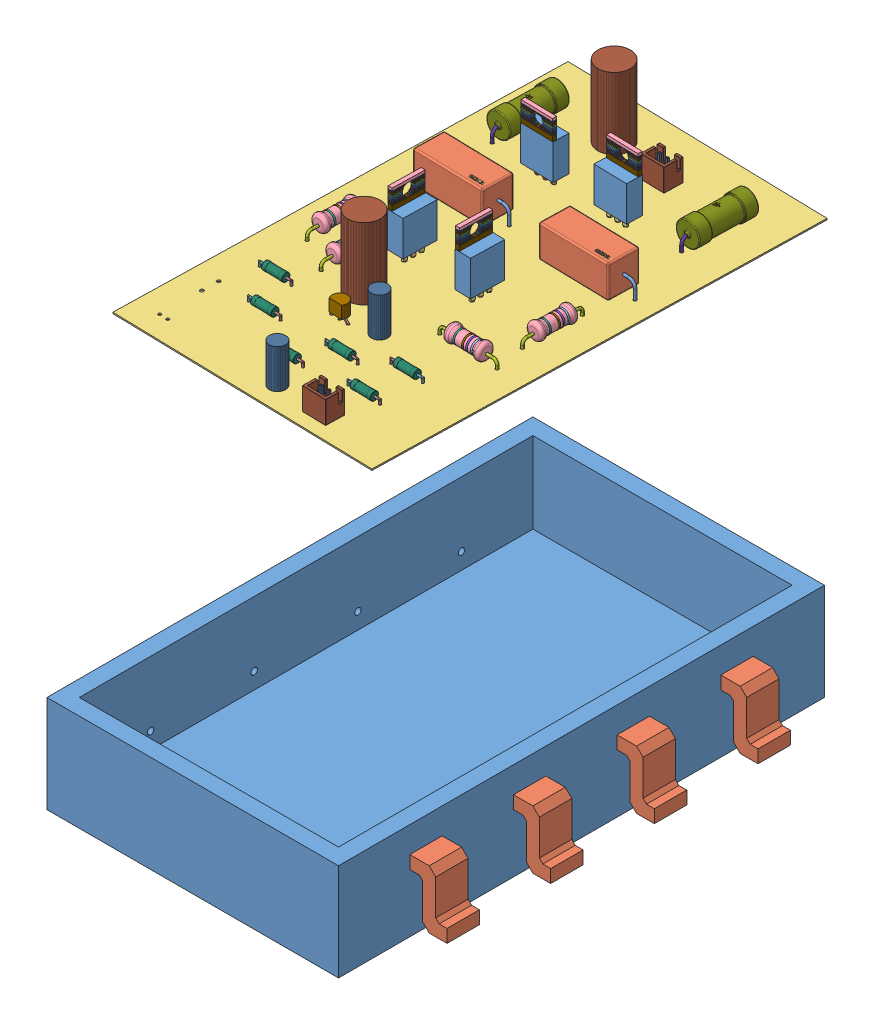
SolidWorks assembly opamp, configuration Default. Lengths in mm.
Overall size (208.13 39 264.23).
474 component instances, 67 part files, 9 mates.
Components (placement in the parent):
- OPAMP_Shyamal-1: OPAMP_Shyamal [Default] at (4.6207 72.5871 193.2104) size (90 30 150)
- OPAMP_PIN-3: OPAMP_PIN [Default] at (6.6207 90.5871 65.2104) x (-1 0 0) z (0 0 -1) size (13.5 18 10)
- OPAMP_PIN-5: OPAMP_PIN [Default] at (6.6207 90.5871 97.2104) x (-1 0 0) z (0 0 -1) size (13.5 18 10)
- OPAMP_PIN-8: OPAMP_PIN [Default] at (6.6207 90.5871 129.2104) x (-1 0 0) z (0 0 -1) size (13.5 18 10)
- OPAMP_PIN-10: OPAMP_PIN [Default] at (6.6207 90.5871 161.2104) x (-1 0 0) z (0 0 -1) size (13.5 18 10)
- OPAMP_PIN-12: OPAMP_PIN [Default] at (92.6207 90.5871 171.2104) size (13.5 18 10)
- OPAMP_PIN-14: OPAMP_PIN [Default] at (92.6207 90.5871 139.2104) size (13.5 18 10)
- OPAMP_PIN-16: OPAMP_PIN [Default] at (92.6207 90.5871 107.2104) size (13.5 18 10)
- OPAMP_PIN-18: OPAMP_PIN [Default] at (92.6207 90.5871 75.2104) size (13.5 18 10)
- PCB1-1: PCB1 [Default] at (-20.1126 88.7696 68.1609) x (0.023644 0 -0.99972) z (0 1 0) size (137.29 81.92 39)
  - PCB1.step-1: PCB1.step [Default] at origin size (137.29 81.92 39)
    - Board.step-1: Board.step [Default] at origin size (137.29 81.92 0.41)
      - Open CASCADE STEP translator 6.8 1.1.1.step-1: Open CASCADE STEP translator 6.8 1.1.1.step [Default] at (0 0 -0.4115) size (137.29 81.92 0.41)
    - R61.step-1: R61.step [Default] at origin size (18.91 5.72 7.96)
      - Res_Yageo_KNP100JR-73-22R_eec.step-1: Res_Yageo_KNP100JR-73-22R_eec.step [Default] at (64.389 10.414 0) x (-1 0 0) z (0 0 1) size (18.91 5.72 7.96)
        - 1.step-1: 1.step [Default] at (0 0 2.55) size (11.5 5.1 5.1)
        - 2.step-1: 2.step [Default] at (-3.2931 0 2.55) x (0 0 -1) z (1 0 0) size (4.2 4.2 0.5)
        - 3.step-1: 3.step [Default] at (2.7931 0 2.55) x (0 -0.492137 0.870518) z (-1 0 0) size (4.2 4.2 0.5)
        - 4.step-1: 4.step [Default] at (0 0 -2.55) size (18.91 0.8 5.21)
        - 5.step-1: 5.step [Default] at (-1.7931 0 2.55) x (0 0 -1) z (1 0 0) size (4.2 4.2 0.5)
        - 6.step-1: 6.step [Default] at (0.0069 0 2.55) x (0 -0.017206 0.999852) z (-1 0 0) size (4.2 4.2 0.5)
    - R51.step-1: R51.step [Default] at origin size (18.91 5.72 7.96)
      - Res_Yageo_KNP100JR-73-22R_eec.step-1: Res_Yageo_KNP100JR-73-22R_eec.step [Default] at (52.832 61.976 0) x (1 0 0) z (0 0 1) size (18.91 5.72 7.96)
        - 1.step-1: 1.step [Default] at (0 0 2.55) size (11.5 5.1 5.1)
        - 2.step-1: 2.step [Default] at (-3.2931 0 2.55) x (0 0 -1) z (1 0 0) size (4.2 4.2 0.5)
        - 3.step-1: 3.step [Default] at (2.7931 0 2.55) x (0 -0.492137 0.870518) z (-1 0 0) size (4.2 4.2 0.5)
        - 4.step-1: 4.step [Default] at (0 0 -2.55) size (18.91 0.8 5.21)
        - 5.step-1: 5.step [Default] at (-1.7931 0 2.55) x (0 0 -1) z (1 0 0) size (4.2 4.2 0.5)
        - 6.step-1: 6.step [Default] at (0.0069 0 2.55) x (0 -0.017206 0.999852) z (-1 0 0) size (4.2 4.2 0.5)
    - output.step-1: output.step [Default] at origin size (5.75 7.4 10.4)
      - Conn_JST_B2B-XH-A_LF_SN_eec.step-1: Conn_JST_B2B-XH-A_LF_SN_eec.step [Default] at (120.887 35.072 0) x (0 -1 0) z (0 0 1) size (7.4 5.75 10.4)
        - 1-0.step-1: 1-0.step [Default] at (0 0.025 0) x (-1 0 0) z (0 1 0) size (7.4 10.4 5.75)
          - 1-1.step-1: 1-1.step [Default] at origin size (3.14 10.2 0.64)
          - B2B-XH-A.step-1: B2B-XH-A.step [Default] at origin size (7.4 7 5.75)
          - JST_Logo_adjustable.step-1: JST_Logo_adjustable.step [Default] at (-1.7267 5.5034 2.841) size (0.85 2.3 0.01)
    - input.step-1: input.step [Default] at origin size (5.75 7.4 10.4)
      - Conn_JST_B2B-XH-A_LF_SN_eec.step-1: Conn_JST_B2B-XH-A_LF_SN_eec.step [Default] at (6.841 22.499 0) x (0 -1 0) z (0 0 1) size (7.4 5.75 10.4)
        - 1-0.step-1: 1-0.step [Default] at (0 0.025 0) x (-1 0 0) z (0 1 0) size (7.4 10.4 5.75)
          - 1-1.step-1: 1-1.step [Default] at origin size (3.14 10.2 0.64)
          - B2B-XH-A.step-1: B2B-XH-A.step [Default] at origin size (7.4 7 5.75)
          - JST_Logo_adjustable.step-1: JST_Logo_adjustable.step [Default] at (-1.7267 5.5034 2.841) size (0.85 2.3 0.01)
    - RE.step-1: RE.step [Default] at origin size (2.5 10.6 6.5)
      - Res_Vishay_BC_Components_MRS25000C1101FCT00_eec.step-1: Res_Vishay_BC_Components_MRS25000C1101FCT00_eec.step [Default] at (30.607 20.955 0) x (0 -1 0) z (0 0 1) size (2.05 0.6 5.55)
      - Res_Vishay_BC_Components_MRS25000C1101FCT00_eec-2.step-1: Res_Vishay_BC_Components_MRS25000C1101FCT00_eec-2.step [Default] at (30.607 20.955 0) x (0 -1 0) z (0 0 1) size (2.05 0.6 5.55)
      - Res_Vishay_BC_Components_MRS25000C1101FCT00_eec-3.step-1: Res_Vishay_BC_Components_MRS25000C1101FCT00_eec-3.step [Default] at (30.607 20.955 0) x (0 -1 0) z (0 0 1) size (6.5 2.5 2.5)
    - RC.step-1: RC.step [Default] at origin size (2.5 10.6 6.5)
      - Res_Vishay_BC_Components_MRS25000C1101FCT00_eec.step-1: Res_Vishay_BC_Components_MRS25000C1101FCT00_eec.step [Default] at (35.179 67.31 0) x (0 1 0) z (0 0 1) size (2.05 0.6 5.55)
      - Res_Vishay_BC_Components_MRS25000C1101FCT00_eec-2.step-1: Res_Vishay_BC_Components_MRS25000C1101FCT00_eec-2.step [Default] at (35.179 67.31 0) x (0 1 0) z (0 0 1) size (2.05 0.6 5.55)
      - Res_Vishay_BC_Components_MRS25000C1101FCT00_eec-3.step-1: Res_Vishay_BC_Components_MRS25000C1101FCT00_eec-3.step [Default] at (35.179 67.31 0) x (0 1 0) z (0 0 1) size (6.5 2.5 2.5)
    - R10.step-1: R10.step [Default] at origin size (22.46 7.5 11.5)
      - Res_Vishay_AC05000003909JAC00_eec.step-1: Res_Vishay_AC05000003909JAC00_eec.step [Default] at (116.459 12.827 0) size (22.46 7.5 11.5)
        - AC0500000XXXJAC00.step-1: AC0500000XXXJAC00.step [Default] at (-37 0 3.75) size (18.87 7.5 7.5)
        - 1-4.step-1: 1-4.step [Default] at (0 0 -8) x (1 0 0) z (0 -1 0) size (22.46 8.15 0.8)
        - 2-5.step-1: 2-5.step [Default] at (-37 0 3.75) size (1.63 1.9 3.41)
    - R9.step-1: R9.step [Default] at origin size (22.46 7.5 11.5)
      - Res_Vishay_AC05000003909JAC00_eec.step-1: Res_Vishay_AC05000003909JAC00_eec.step [Default] at (114.935 71.12 0) x (-1 0 0) z (0 0 1) size (22.46 7.5 11.5)
        - AC0500000XXXJAC00.step-1: AC0500000XXXJAC00.step [Default] at (-37 0 3.75) size (18.87 7.5 7.5)
        - 1-4.step-1: 1-4.step [Default] at (0 0 -8) x (1 0 0) z (0 -1 0) size (22.46 8.15 0.8)
        - 2-5.step-1: 2-5.step [Default] at (-37 0 3.75) size (1.63 1.9 3.41)
    - R8.step-1: R8.step [Default] at origin size (9.5 29.91 14)
      - Res_Yageo_SQP500JB-1R2_eec.step-1: Res_Yageo_SQP500JB-1R2_eec.step [Default] at (85.217 60.452 0) x (0 1 0) z (0 0 1) size (29.91 9.5 14)
        - 1-6.step-1: 1-6.step [Default] at origin size (29.91 0.8 9.4)
        - 2-7.step-1: 2-7.step [Default] at origin size (22 9.5 10)
        - Yageo_Logo.step-1: Yageo_Logo.step [Default] at (-8.1443 3.6121 9.991) size (4.52 1.05 0.01)
    - R7.step-1: R7.step [Default] at origin size (9.5 29.91 14)
      - Res_Yageo_SQP500JB-1R2_eec.step-1: Res_Yageo_SQP500JB-1R2_eec.step [Default] at (85.725 21.209 0) x (0 1 0) z (0 0 1) size (29.91 9.5 14)
        - 1-6.step-1: 1-6.step [Default] at origin size (29.91 0.8 9.4)
        - 2-7.step-1: 2-7.step [Default] at origin size (22 9.5 10)
        - Yageo_Logo.step-1: Yageo_Logo.step [Default] at (-8.1443 3.6121 9.991) size (4.52 1.05 0.01)
    - R6.step-1: R6.step [Default] at origin size (5.72 18.91 7.96)
      - Res_Yageo_KNP100JR-73-22R_eec.step-1: Res_Yageo_KNP100JR-73-22R_eec.step [Default] at (45.974 17.653 0) x (0 1 0) z (0 0 1) size (18.91 5.72 7.96)
        - 1.step-1: 1.step [Default] at (0 0 2.55) size (11.5 5.1 5.1)
        - 2.step-1: 2.step [Default] at (-3.2931 0 2.55) x (0 0 -1) z (1 0 0) size (4.2 4.2 0.5)
        - 3.step-1: 3.step [Default] at (2.7931 0 2.55) x (0 -0.492137 0.870518) z (-1 0 0) size (4.2 4.2 0.5)
        - 4.step-1: 4.step [Default] at (0 0 -2.55) size (18.91 0.8 5.21)
        - 5.step-1: 5.step [Default] at (-1.7931 0 2.55) x (0 0 -1) z (1 0 0) size (4.2 4.2 0.5)
        - 6.step-1: 6.step [Default] at (0.0069 0 2.55) x (0 -0.017206 0.999852) z (-1 0 0) size (4.2 4.2 0.5)
    - R5.step-1: R5.step [Default] at origin size (18.91 5.72 7.96)
      - Res_Yageo_KNP100JR-73-22R_eec.step-1: Res_Yageo_KNP100JR-73-22R_eec.step [Default] at (58.547 72.39 0) x (-1 0 0) z (0 0 1) size (18.91 5.72 7.96)
        - 1.step-1: 1.step [Default] at (0 0 2.55) size (11.5 5.1 5.1)
        - 2.step-1: 2.step [Default] at (-3.2931 0 2.55) x (0 0 -1) z (1 0 0) size (4.2 4.2 0.5)
        - 3.step-1: 3.step [Default] at (2.7931 0 2.55) x (0 -0.492137 0.870518) z (-1 0 0) size (4.2 4.2 0.5)
        - 4.step-1: 4.step [Default] at (0 0 -2.55) size (18.91 0.8 5.21)
        - 5.step-1: 5.step [Default] at (-1.7931 0 2.55) x (0 0 -1) z (1 0 0) size (4.2 4.2 0.5)
        - 6.step-1: 6.step [Default] at (0.0069 0 2.55) x (0 -0.017206 0.999852) z (-1 0 0) size (4.2 4.2 0.5)
    - R4.step-1: R4.step [Default] at origin size (2.5 10.6 6.5)
      - Res_Vishay_BC_Components_MRS25000C1101FCT00_eec.step-1: Res_Vishay_BC_Components_MRS25000C1101FCT00_eec.step [Default] at (18.161 21.463 0) x (0 1 0) z (0 0 1) size (2.05 0.6 5.55)
      - Res_Vishay_BC_Components_MRS25000C1101FCT00_eec-2.step-1: Res_Vishay_BC_Components_MRS25000C1101FCT00_eec-2.step [Default] at (18.161 21.463 0) x (0 1 0) z (0 0 1) size (2.05 0.6 5.55)
      - Res_Vishay_BC_Components_MRS25000C1101FCT00_eec-3.step-1: Res_Vishay_BC_Components_MRS25000C1101FCT00_eec-3.step [Default] at (18.161 21.463 0) x (0 1 0) z (0 0 1) size (6.5 2.5 2.5)
    - R3.step-1: R3.step [Default] at origin size (2.5 10.6 6.5)
      - Res_Vishay_BC_Components_MRS25000C1101FCT00_eec.step-1: Res_Vishay_BC_Components_MRS25000C1101FCT00_eec.step [Default] at (25.146 35.814 0) x (0 1 0) z (0 0 1) size (2.05 0.6 5.55)
      - Res_Vishay_BC_Components_MRS25000C1101FCT00_eec-2.step-1: Res_Vishay_BC_Components_MRS25000C1101FCT00_eec-2.step [Default] at (25.146 35.814 0) x (0 1 0) z (0 0 1) size (2.05 0.6 5.55)
      - Res_Vishay_BC_Components_MRS25000C1101FCT00_eec-3.step-1: Res_Vishay_BC_Components_MRS25000C1101FCT00_eec-3.step [Default] at (25.146 35.814 0) x (0 1 0) z (0 0 1) size (6.5 2.5 2.5)
    - R2.step-1: R2.step [Default] at origin size (2.5 10.6 6.5)
      - Res_Vishay_BC_Components_MRS25000C1101FCT00_eec.step-1: Res_Vishay_BC_Components_MRS25000C1101FCT00_eec.step [Default] at (24.384 59.436 0) x (0 1 0) z (0 0 1) size (2.05 0.6 5.55)
      - Res_Vishay_BC_Components_MRS25000C1101FCT00_eec-2.step-1: Res_Vishay_BC_Components_MRS25000C1101FCT00_eec-2.step [Default] at (24.384 59.436 0) x (0 1 0) z (0 0 1) size (2.05 0.6 5.55)
      - Res_Vishay_BC_Components_MRS25000C1101FCT00_eec-3.step-1: Res_Vishay_BC_Components_MRS25000C1101FCT00_eec-3.step [Default] at (24.384 59.436 0) x (0 1 0) z (0 0 1) size (6.5 2.5 2.5)
    - R1.step-1: R1.step [Default] at origin size (2.5 10.6 6.5)
      - Res_Vishay_BC_Components_MRS25000C1101FCT00_eec.step-1: Res_Vishay_BC_Components_MRS25000C1101FCT00_eec.step [Default] at (15.748 43.307 0) x (0 1 0) z (0 0 1) size (2.05 0.6 5.55)
      - Res_Vishay_BC_Components_MRS25000C1101FCT00_eec-2.step-1: Res_Vishay_BC_Components_MRS25000C1101FCT00_eec-2.step [Default] at (15.748 43.307 0) x (0 1 0) z (0 0 1) size (2.05 0.6 5.55)
      - Res_Vishay_BC_Components_MRS25000C1101FCT00_eec-3.step-1: Res_Vishay_BC_Components_MRS25000C1101FCT00_eec-3.step [Default] at (15.748 43.307 0) x (0 1 0) z (0 0 1) size (6.5 2.5 2.5)
    - Q5.step-1: Q5.step [Default] at origin size (4.85 10.3 21.45)
      - 6100337184.step-1: 6100337184.step [Default] at (105.55 30.861 18.98) size (1.25 9.95 0.87)
        - Extruded.step-1: Extruded.step [Default] at origin size (1.25 9.95 0.87)
      - 6100336784.step-1: 6100336784.step [Default] at (105.55 27.411 17.05) size (1.25 3.05 0.38)
        - Extruded-8.step-1: Extruded-8.step [Default] at origin size (1.25 3.05 0.38)
      - 6100336784.step-2: 6100336784.step [Default] at (105.55 34.311 17.05) size (1.25 3.05 0.38)
        - Extruded-8.step-1: Extruded-8.step [Default] at origin size (1.25 3.05 0.38)
      - 6100335504.step-1: 6100335504.step [Default] at (105.55 27.411 16.67) size (1.25 3.05 0.38)
        - Extruded-9.step-1: Extruded-9.step [Default] at origin size (1.25 3.05 0.38)
      - 6100335504.step-2: 6100335504.step [Default] at (105.55 34.311 16.67) size (1.25 3.05 0.38)
        - Extruded-9.step-1: Extruded-9.step [Default] at origin size (1.25 3.05 0.38)
      - 6100342224.step-1: 6100342224.step [Default] at (105.55 27.4295 17.43) size (1.25 3.09 0.36)
        - Extruded-10.step-1: Extruded-10.step [Default] at origin size (1.25 3.09 0.36)
      - 6100342224.step-2: 6100342224.step [Default] at (105.55 34.2925 17.43) size (1.25 3.09 0.36)
        - Extruded-10.step-1: Extruded-10.step [Default] at origin size (1.25 3.09 0.36)
      - 6100331024.step-1: 6100331024.step [Default] at (105.55 27.4295 16.31) size (1.25 3.09 0.37)
        - Extruded-11.step-1: Extruded-11.step [Default] at origin size (1.25 3.09 0.37)
      - 6100331024.step-2: 6100331024.step [Default] at (105.55 34.2925 16.31) size (1.25 3.09 0.37)
        - Extruded-11.step-1: Extruded-11.step [Default] at origin size (1.25 3.09 0.37)
      - 6100330544.step-1: 6100330544.step [Default] at (105.55 27.4843 17.79) size (1.25 3.2 0.33)
        - Extruded-12.step-1: Extruded-12.step [Default] at origin size (1.25 3.2 0.33)
      - 6100330544.step-2: 6100330544.step [Default] at (105.55 34.2377 17.79) size (1.25 3.2 0.33)
        - Extruded-12.step-1: Extruded-12.step [Default] at origin size (1.25 3.2 0.33)
      - 6100330224.step-1: 6100330224.step [Default] at (105.55 27.4843 15.98) size (1.25 3.2 0.34)
        - Extruded-13.step-1: Extruded-13.step [Default] at origin size (1.25 3.2 0.34)
      - 6100330224.step-2: 6100330224.step [Default] at (105.55 34.2377 15.98) size (1.25 3.2 0.34)
        - Extruded-13.step-1: Extruded-13.step [Default] at origin size (1.25 3.2 0.34)
      - 6100325984.step-1: 6100325984.step [Default] at (105.55 27.5732 18.12) size (1.25 3.37 0.3)
        - Extruded-14.step-1: Extruded-14.step [Default] at origin size (1.25 3.37 0.3)
      - 6100325984.step-2: 6100325984.step [Default] at (105.55 34.1488 18.12) size (1.25 3.37 0.3)
        - Extruded-14.step-1: Extruded-14.step [Default] at origin size (1.25 3.37 0.3)
      - 6100325984.step-3: 6100325984.step [Default] at (105.55 27.5732 15.69) size (1.25 3.37 0.3)
        - Extruded-14.step-1: Extruded-14.step [Default] at origin size (1.25 3.37 0.3)
      - 6100325984.step-4: 6100325984.step [Default] at (105.55 34.1488 15.69) size (1.25 3.37 0.3)
        - Extruded-14.step-1: Extruded-14.step [Default] at origin size (1.25 3.37 0.3)
      - 6100325824.step-1: 6100325824.step [Default] at (105.55 27.6929 18.41) size (1.25 3.61 0.25)
        - Extruded-15.step-1: Extruded-15.step [Default] at origin size (1.25 3.61 0.25)
      - 6100325824.step-2: 6100325824.step [Default] at (105.55 34.0291 18.41) size (1.25 3.61 0.25)
        - Extruded-15.step-1: Extruded-15.step [Default] at origin size (1.25 3.61 0.25)
      - 6100326864.step-1: 6100326864.step [Default] at (105.55 27.6929 15.45) size (1.25 3.61 0.24)
        - Extruded-16.step-1: Extruded-16.step [Default] at origin size (1.25 3.61 0.24)
      - 6100326864.step-2: 6100326864.step [Default] at (105.55 34.0291 15.45) size (1.25 3.61 0.24)
        - Extruded-16.step-1: Extruded-16.step [Default] at origin size (1.25 3.61 0.24)
      - 6100326304.step-1: 6100326304.step [Default] at (105.55 27.8388 18.65) size (1.25 3.91 0.18)
        - Extruded-17.step-1: Extruded-17.step [Default] at origin size (1.25 3.91 0.18)
      - 6100326304.step-2: 6100326304.step [Default] at (105.55 33.8832 18.65) size (1.25 3.91 0.18)
        - Extruded-17.step-1: Extruded-17.step [Default] at origin size (1.25 3.91 0.18)
      - 6100326304.step-3: 6100326304.step [Default] at (105.55 27.8388 15.27) size (1.25 3.91 0.18)
        - Extruded-17.step-1: Extruded-17.step [Default] at origin size (1.25 3.91 0.18)
      - 6100326304.step-4: 6100326304.step [Default] at (105.55 33.8832 15.27) size (1.25 3.91 0.18)
        - Extruded-17.step-1: Extruded-17.step [Default] at origin size (1.25 3.91 0.18)
      - 6100326704.step-1: 6100326704.step [Default] at (105.55 28.0052 18.83) size (1.25 4.24 0.11)
        - Extruded-18.step-1: Extruded-18.step [Default] at origin size (1.25 4.24 0.11)
      - 6100326704.step-2: 6100326704.step [Default] at (105.55 33.7168 18.83) size (1.25 4.24 0.11)
        - Extruded-18.step-1: Extruded-18.step [Default] at origin size (1.25 4.24 0.11)
      - 6100327504.step-1: 6100327504.step [Default] at (105.55 28.0052 15.16) size (1.25 4.24 0.12)
        - Extruded-19.step-1: Extruded-19.step [Default] at origin size (1.25 4.24 0.12)
      - 6100327504.step-2: 6100327504.step [Default] at (105.55 33.7168 15.16) size (1.25 4.24 0.12)
        - Extruded-19.step-1: Extruded-19.step [Default] at origin size (1.25 4.24 0.12)
      - 6100327344.step-1: 6100327344.step [Default] at (105.55 28.1857 18.94) size (1.25 4.6 0.04)
        - Extruded-20.step-1: Extruded-20.step [Default] at origin size (1.25 4.6 0.04)
      - 6100327344.step-2: 6100327344.step [Default] at (105.55 33.5363 18.94) size (1.25 4.6 0.04)
        - Extruded-20.step-1: Extruded-20.step [Default] at origin size (1.25 4.6 0.04)
      - 6100327344.step-3: 6100327344.step [Default] at (105.55 28.1857 15.13) size (1.25 4.6 0.04)
        - Extruded-20.step-1: Extruded-20.step [Default] at origin size (1.25 4.6 0.04)
      - 6100327344.step-4: 6100327344.step [Default] at (105.55 33.5363 15.13) size (1.25 4.6 0.04)
        - Extruded-20.step-1: Extruded-20.step [Default] at origin size (1.25 4.6 0.04)
      - 6100330864.step-1: 6100330864.step [Default] at (105.55 30.861 13.65) size (1.25 9.95 1.48)
        - Extruded-21.step-1: Extruded-21.step [Default] at origin size (1.25 9.95 1.48)
      - 6100331424.step-1: 6100331424.step [Default] at (103.75 30.861 2.8) size (4.85 10.3 10.85)
        - Extruded-22.step-1: Extruded-22.step [Default] at origin size (4.85 10.3 10.85)
      - 6100325584.step-1: 6100325584.step [Default] at (103.505 28.321 -1.6) size (0.5 0.78 1.6)
        - Extruded-23.step-1: Extruded-23.step [Default] at origin size (0.5 0.78 1.6)
      - 6138241984.step-1: 6138241984.step [Default] at (103.505 28.321 0) size (0.5 1.34 2.8)
        - Extruded-24.step-1: Extruded-24.step [Default] at origin size (0.5 1.34 2.8)
      - 6100325584.step-2: 6100325584.step [Default] at (103.505 30.861 -1.6) size (0.5 0.78 1.6)
        - Extruded-23.step-1: Extruded-23.step [Default] at origin size (0.5 0.78 1.6)
      - 6138241984.step-2: 6138241984.step [Default] at (103.505 30.861 0) size (0.5 1.34 2.8)
        - Extruded-24.step-1: Extruded-24.step [Default] at origin size (0.5 1.34 2.8)
      - 6100325584.step-3: 6100325584.step [Default] at (103.505 33.401 -1.6) size (0.5 0.78 1.6)
        - Extruded-23.step-1: Extruded-23.step [Default] at origin size (0.5 0.78 1.6)
      - 6138241984.step-3: 6138241984.step [Default] at (103.505 33.401 0) size (0.5 1.34 2.8)
        - Extruded-24.step-1: Extruded-24.step [Default] at origin size (0.5 1.34 2.8)
    - Q4.step-1: Q4.step [Default] at origin size (10.3 4.85 21.45)
      - 6138241504.step-1: 6138241504.step [Default] at (62.357 33.033 18.98) size (9.95 1.25 0.87)
        - Extruded-25.step-1: Extruded-25.step [Default] at origin size (9.95 1.25 0.87)
      - 6138241344.step-1: 6138241344.step [Default] at (65.807 33.033 17.05) size (3.05 1.25 0.38)
        - Extruded-26.step-1: Extruded-26.step [Default] at origin size (3.05 1.25 0.38)
      - 6138241344.step-2: 6138241344.step [Default] at (58.907 33.033 17.05) size (3.05 1.25 0.38)
        - Extruded-26.step-1: Extruded-26.step [Default] at origin size (3.05 1.25 0.38)
      - 6138241104.step-1: 6138241104.step [Default] at (65.807 33.033 16.67) size (3.05 1.25 0.38)
        - Extruded-27.step-1: Extruded-27.step [Default] at origin size (3.05 1.25 0.38)
      - 6138241104.step-2: 6138241104.step [Default] at (58.907 33.033 16.67) size (3.05 1.25 0.38)
        - Extruded-27.step-1: Extruded-27.step [Default] at origin size (3.05 1.25 0.38)
      - 6138240864.step-1: 6138240864.step [Default] at (65.7885 33.033 17.43) size (3.09 1.25 0.36)
        - Extruded-28.step-1: Extruded-28.step [Default] at origin size (3.09 1.25 0.36)
      - 6138240864.step-2: 6138240864.step [Default] at (58.9255 33.033 17.43) size (3.09 1.25 0.36)
        - Extruded-28.step-1: Extruded-28.step [Default] at origin size (3.09 1.25 0.36)
      - 6138240624.step-1: 6138240624.step [Default] at (65.7885 33.033 16.31) size (3.09 1.25 0.37)
        - Extruded-29.step-1: Extruded-29.step [Default] at origin size (3.09 1.25 0.37)
      - 6138240624.step-2: 6138240624.step [Default] at (58.9255 33.033 16.31) size (3.09 1.25 0.37)
        - Extruded-29.step-1: Extruded-29.step [Default] at origin size (3.09 1.25 0.37)
      - 6138240384.step-1: 6138240384.step [Default] at (65.7337 33.033 17.79) size (3.2 1.25 0.33)
        - Extruded-30.step-1: Extruded-30.step [Default] at origin size (3.2 1.25 0.33)
      - 6138240384.step-2: 6138240384.step [Default] at (58.9803 33.033 17.79) size (3.2 1.25 0.33)
        - Extruded-30.step-1: Extruded-30.step [Default] at origin size (3.2 1.25 0.33)
      - 6138240144.step-1: 6138240144.step [Default] at (65.7337 33.033 15.98) size (3.2 1.25 0.34)
        - Extruded-31.step-1: Extruded-31.step [Default] at origin size (3.2 1.25 0.34)
      - 6138240144.step-2: 6138240144.step [Default] at (58.9803 33.033 15.98) size (3.2 1.25 0.34)
        - Extruded-31.step-1: Extruded-31.step [Default] at origin size (3.2 1.25 0.34)
      - 6138239904.step-1: 6138239904.step [Default] at (65.6448 33.033 18.12) size (3.37 1.25 0.3)
        - Extruded-32.step-1: Extruded-32.step [Default] at origin size (3.37 1.25 0.3)
      - 6138239904.step-2: 6138239904.step [Default] at (59.0692 33.033 18.12) size (3.37 1.25 0.3)
        - Extruded-32.step-1: Extruded-32.step [Default] at origin size (3.37 1.25 0.3)
      - 6138239904.step-3: 6138239904.step [Default] at (65.6448 33.033 15.69) size (3.37 1.25 0.3)
        - Extruded-32.step-1: Extruded-32.step [Default] at origin size (3.37 1.25 0.3)
      - 6138239904.step-4: 6138239904.step [Default] at (59.0692 33.033 15.69) size (3.37 1.25 0.3)
        - Extruded-32.step-1: Extruded-32.step [Default] at origin size (3.37 1.25 0.3)
      - 6138239504.step-1: 6138239504.step [Default] at (65.5251 33.033 18.41) size (3.61 1.25 0.25)
        - Extruded-33.step-1: Extruded-33.step [Default] at origin size (3.61 1.25 0.25)
      - 6138239504.step-2: 6138239504.step [Default] at (59.1889 33.033 18.41) size (3.61 1.25 0.25)
        - Extruded-33.step-1: Extruded-33.step [Default] at origin size (3.61 1.25 0.25)
      - 6138239264.step-1: 6138239264.step [Default] at (65.5251 33.033 15.45) size (3.61 1.25 0.24)
        - Extruded-34.step-1: Extruded-34.step [Default] at origin size (3.61 1.25 0.24)
      - 6138239264.step-2: 6138239264.step [Default] at (59.1889 33.033 15.45) size (3.61 1.25 0.24)
        - Extruded-34.step-1: Extruded-34.step [Default] at origin size (3.61 1.25 0.24)
      - 6138239024.step-1: 6138239024.step [Default] at (65.3792 33.033 18.65) size (3.91 1.25 0.18)
        - Extruded-35.step-1: Extruded-35.step [Default] at origin size (3.91 1.25 0.18)
      - 6138239024.step-2: 6138239024.step [Default] at (59.3348 33.033 18.65) size (3.91 1.25 0.18)
        - Extruded-35.step-1: Extruded-35.step [Default] at origin size (3.91 1.25 0.18)
      - 6138239024.step-3: 6138239024.step [Default] at (65.3792 33.033 15.27) size (3.91 1.25 0.18)
        - Extruded-35.step-1: Extruded-35.step [Default] at origin size (3.91 1.25 0.18)
      - 6138239024.step-4: 6138239024.step [Default] at (59.3348 33.033 15.27) size (3.91 1.25 0.18)
        - Extruded-35.step-1: Extruded-35.step [Default] at origin size (3.91 1.25 0.18)
      - 6138238624.step-1: 6138238624.step [Default] at (65.2128 33.033 18.83) size (4.24 1.25 0.11)
        - Extruded-36.step-1: Extruded-36.step [Default] at origin size (4.24 1.25 0.11)
      - 6138238624.step-2: 6138238624.step [Default] at (59.5012 33.033 18.83) size (4.24 1.25 0.11)
        - Extruded-36.step-1: Extruded-36.step [Default] at origin size (4.24 1.25 0.11)
      - 6138238384.step-1: 6138238384.step [Default] at (65.2128 33.033 15.16) size (4.24 1.25 0.12)
        - Extruded-37.step-1: Extruded-37.step [Default] at origin size (4.24 1.25 0.12)
      - 6138238384.step-2: 6138238384.step [Default] at (59.5012 33.033 15.16) size (4.24 1.25 0.12)
        - Extruded-37.step-1: Extruded-37.step [Default] at origin size (4.24 1.25 0.12)
      - 6138238144.step-1: 6138238144.step [Default] at (65.0323 33.033 18.94) size (4.6 1.25 0.04)
        - Extruded-38.step-1: Extruded-38.step [Default] at origin size (4.6 1.25 0.04)
      - 6138238144.step-2: 6138238144.step [Default] at (59.6817 33.033 18.94) size (4.6 1.25 0.04)
        - Extruded-38.step-1: Extruded-38.step [Default] at origin size (4.6 1.25 0.04)
      - 6138238144.step-3: 6138238144.step [Default] at (65.0323 33.033 15.13) size (4.6 1.25 0.04)
        - Extruded-38.step-1: Extruded-38.step [Default] at origin size (4.6 1.25 0.04)
      - 6138238144.step-4: 6138238144.step [Default] at (59.6817 33.033 15.13) size (4.6 1.25 0.04)
        - Extruded-38.step-1: Extruded-38.step [Default] at origin size (4.6 1.25 0.04)
      - 6138237744.step-1: 6138237744.step [Default] at (62.357 33.033 13.65) size (9.95 1.25 1.48)
        - Extruded-39.step-1: Extruded-39.step [Default] at origin size (9.95 1.25 1.48)
      - 6138237584.step-1: 6138237584.step [Default] at (62.357 31.233 2.8) size (10.3 4.85 10.85)
        - Extruded-40.step-1: Extruded-40.step [Default] at origin size (10.3 4.85 10.85)
      - 6138237424.step-1: 6138237424.step [Default] at (64.897 30.988 -1.6) size (0.78 0.5 1.6)
        - Extruded-41.step-1: Extruded-41.step [Default] at origin size (0.78 0.5 1.6)
      - 6138237264.step-1: 6138237264.step [Default] at (64.897 30.988 0) size (1.34 0.5 2.8)
        - Extruded-42.step-1: Extruded-42.step [Default] at origin size (1.34 0.5 2.8)
      - 6138237424.step-2: 6138237424.step [Default] at (62.357 30.988 -1.6) size (0.78 0.5 1.6)
        - Extruded-41.step-1: Extruded-41.step [Default] at origin size (0.78 0.5 1.6)
      - 6138237264.step-2: 6138237264.step [Default] at (62.357 30.988 0) size (1.34 0.5 2.8)
        - Extruded-42.step-1: Extruded-42.step [Default] at origin size (1.34 0.5 2.8)
      - 6138237424.step-3: 6138237424.step [Default] at (59.817 30.988 -1.6) size (0.78 0.5 1.6)
        - Extruded-41.step-1: Extruded-41.step [Default] at origin size (0.78 0.5 1.6)
      - 6138237264.step-3: 6138237264.step [Default] at (59.817 30.988 0) size (1.34 0.5 2.8)
        - Extruded-42.step-1: Extruded-42.step [Default] at origin size (1.34 0.5 2.8)
    - Q3.step-1: Q3.step [Default] at origin size (3.69 5.68 14.04)
      - PCB3.step-1: PCB3.step [Default] at (34.0361 45.8469 4) x (0 -1 0) z (0 0 1) size (5.68 0.46 12.71)
        - Free-Models.step-1: Free-Models.step [Default] at origin size (5.68 0.46 12.71)
          - PCB1.step-1: PCB1.step [Default] at (-1.2706 -0.1276 0) x (1 0 0) z (0 -1 0) size (1.81 12.71 0.46)
            - Free-Models-1.step-1: Free-Models-1.step [Default] at origin size (1.81 12.71 0.46)
              - 523779104.step-1: 523779104.step [Default] at (-0.665 -6.35 -0.35) size (1.81 12.71 0.46)
                - Extruded-43.step-1: Extruded-43.step [Default] at origin size (1.81 12.71 0.46)
            - Board-44.step-1: Board-44.step [Default] at (0 0 -0.2083) size (0.27 0.27 0.21)
          - PCB2.step-1: PCB2.step [Default] at (0.0004 -0.1275 0) x (1 0 0) z (0 -1 0) size (0.47 12.7 0.45)
            - Free-Models-2.step-1: Free-Models-2.step [Default] at origin size (0.47 12.7 0.45)
              - 790454240.step-1: 790454240.step [Default] at (0 -6.35 -0.35) size (0.47 12.7 0.45)
                - Extruded-45.step-1: Extruded-45.step [Default] at origin size (0.47 12.7 0.45)
            - Board-46.step-1: Board-46.step [Default] at (0 0 -0.2083) size (0.27 0.27 0.21)
          - PCB1.step-2: PCB1.step [Default] at (1.2705 0.1276 0) x (-1 0 0) z (0 1 0) size (1.81 12.71 0.46)
            - Free-Models-1.step-1: Free-Models-1.step [Default] at origin size (1.81 12.71 0.46)
              - 523779104.step-1: 523779104.step [Default] at (-0.665 -6.35 -0.35) size (1.81 12.71 0.46)
                - Extruded-43.step-1: Extruded-43.step [Default] at origin size (1.81 12.71 0.46)
            - Board-44.step-1: Board-44.step [Default] at (0 0 -0.2083) size (0.27 0.27 0.21)
        - Board-47.step-1: Board-47.step [Default] at (0 0 -0.2083) size (0.31 0.31 0.21)
      - 6100335024.step-1: 6100335024.step [Default] at (34.5437 45.847 1.5) size (3.69 4.72 3.83)
        - Extruded-48.step-1: Extruded-48.step [Default] at origin size (3.69 4.72 3.83)
    - Q2.step-1: Q2.step [Default] at origin size (10.3 4.85 21.45)
      - 6138241504.step-1: 6138241504.step [Default] at (62.103 54.115 18.98) size (9.95 1.25 0.87)
        - Extruded-25.step-1: Extruded-25.step [Default] at origin size (9.95 1.25 0.87)
      - 6138241344.step-1: 6138241344.step [Default] at (65.553 54.115 17.05) size (3.05 1.25 0.38)
        - Extruded-26.step-1: Extruded-26.step [Default] at origin size (3.05 1.25 0.38)
      - 6138241344.step-2: 6138241344.step [Default] at (58.653 54.115 17.05) size (3.05 1.25 0.38)
        - Extruded-26.step-1: Extruded-26.step [Default] at origin size (3.05 1.25 0.38)
      - 6138241104.step-1: 6138241104.step [Default] at (65.553 54.115 16.67) size (3.05 1.25 0.38)
        - Extruded-27.step-1: Extruded-27.step [Default] at origin size (3.05 1.25 0.38)
      - 6138241104.step-2: 6138241104.step [Default] at (58.653 54.115 16.67) size (3.05 1.25 0.38)
        - Extruded-27.step-1: Extruded-27.step [Default] at origin size (3.05 1.25 0.38)
      - 6138240864.step-1: 6138240864.step [Default] at (65.5345 54.115 17.43) size (3.09 1.25 0.36)
        - Extruded-28.step-1: Extruded-28.step [Default] at origin size (3.09 1.25 0.36)
      - 6138240864.step-2: 6138240864.step [Default] at (58.6715 54.115 17.43) size (3.09 1.25 0.36)
        - Extruded-28.step-1: Extruded-28.step [Default] at origin size (3.09 1.25 0.36)
      - 6138240624.step-1: 6138240624.step [Default] at (65.5345 54.115 16.31) size (3.09 1.25 0.37)
        - Extruded-29.step-1: Extruded-29.step [Default] at origin size (3.09 1.25 0.37)
      - 6138240624.step-2: 6138240624.step [Default] at (58.6715 54.115 16.31) size (3.09 1.25 0.37)
        - Extruded-29.step-1: Extruded-29.step [Default] at origin size (3.09 1.25 0.37)
      - 6138240384.step-1: 6138240384.step [Default] at (65.4797 54.115 17.79) size (3.2 1.25 0.33)
        - Extruded-30.step-1: Extruded-30.step [Default] at origin size (3.2 1.25 0.33)
      - 6138240384.step-2: 6138240384.step [Default] at (58.7263 54.115 17.79) size (3.2 1.25 0.33)
        - Extruded-30.step-1: Extruded-30.step [Default] at origin size (3.2 1.25 0.33)
      - 6138240144.step-1: 6138240144.step [Default] at (65.4797 54.115 15.98) size (3.2 1.25 0.34)
        - Extruded-31.step-1: Extruded-31.step [Default] at origin size (3.2 1.25 0.34)
      - 6138240144.step-2: 6138240144.step [Default] at (58.7263 54.115 15.98) size (3.2 1.25 0.34)
        - Extruded-31.step-1: Extruded-31.step [Default] at origin size (3.2 1.25 0.34)
      - 6138239904.step-1: 6138239904.step [Default] at (65.3908 54.115 18.12) size (3.37 1.25 0.3)
        - Extruded-32.step-1: Extruded-32.step [Default] at origin size (3.37 1.25 0.3)
      - 6138239904.step-2: 6138239904.step [Default] at (58.8152 54.115 18.12) size (3.37 1.25 0.3)
        - Extruded-32.step-1: Extruded-32.step [Default] at origin size (3.37 1.25 0.3)
      - 6138239904.step-3: 6138239904.step [Default] at (65.3908 54.115 15.69) size (3.37 1.25 0.3)
        - Extruded-32.step-1: Extruded-32.step [Default] at origin size (3.37 1.25 0.3)
      - 6138239904.step-4: 6138239904.step [Default] at (58.8152 54.115 15.69) size (3.37 1.25 0.3)
        - Extruded-32.step-1: Extruded-32.step [Default] at origin size (3.37 1.25 0.3)
      - 6138239504.step-1: 6138239504.step [Default] at (65.2711 54.115 18.41) size (3.61 1.25 0.25)
        - Extruded-33.step-1: Extruded-33.step [Default] at origin size (3.61 1.25 0.25)
      - 6138239504.step-2: 6138239504.step [Default] at (58.9349 54.115 18.41) size (3.61 1.25 0.25)
        - Extruded-33.step-1: Extruded-33.step [Default] at origin size (3.61 1.25 0.25)
      - 6138239264.step-1: 6138239264.step [Default] at (65.2711 54.115 15.45) size (3.61 1.25 0.24)
        - Extruded-34.step-1: Extruded-34.step [Default] at origin size (3.61 1.25 0.24)
      - 6138239264.step-2: 6138239264.step [Default] at (58.9349 54.115 15.45) size (3.61 1.25 0.24)
        - Extruded-34.step-1: Extruded-34.step [Default] at origin size (3.61 1.25 0.24)
      - 6138239024.step-1: 6138239024.step [Default] at (65.1252 54.115 18.65) size (3.91 1.25 0.18)
        - Extruded-35.step-1: Extruded-35.step [Default] at origin size (3.91 1.25 0.18)
      - 6138239024.step-2: 6138239024.step [Default] at (59.0808 54.115 18.65) size (3.91 1.25 0.18)
        - Extruded-35.step-1: Extruded-35.step [Default] at origin size (3.91 1.25 0.18)
      - 6138239024.step-3: 6138239024.step [Default] at (65.1252 54.115 15.27) size (3.91 1.25 0.18)
        - Extruded-35.step-1: Extruded-35.step [Default] at origin size (3.91 1.25 0.18)
      - 6138239024.step-4: 6138239024.step [Default] at (59.0808 54.115 15.27) size (3.91 1.25 0.18)
        - Extruded-35.step-1: Extruded-35.step [Default] at origin size (3.91 1.25 0.18)
      - 6138238624.step-1: 6138238624.step [Default] at (64.9588 54.115 18.83) size (4.24 1.25 0.11)
        - Extruded-36.step-1: Extruded-36.step [Default] at origin size (4.24 1.25 0.11)
      - 6138238624.step-2: 6138238624.step [Default] at (59.2472 54.115 18.83) size (4.24 1.25 0.11)
        - Extruded-36.step-1: Extruded-36.step [Default] at origin size (4.24 1.25 0.11)
      - 6138238384.step-1: 6138238384.step [Default] at (64.9588 54.115 15.16) size (4.24 1.25 0.12)
        - Extruded-37.step-1: Extruded-37.step [Default] at origin size (4.24 1.25 0.12)
      - 6138238384.step-2: 6138238384.step [Default] at (59.2472 54.115 15.16) size (4.24 1.25 0.12)
        - Extruded-37.step-1: Extruded-37.step [Default] at origin size (4.24 1.25 0.12)
      - 6138238144.step-1: 6138238144.step [Default] at (64.7783 54.115 18.94) size (4.6 1.25 0.04)
        - Extruded-38.step-1: Extruded-38.step [Default] at origin size (4.6 1.25 0.04)
      - 6138238144.step-2: 6138238144.step [Default] at (59.4277 54.115 18.94) size (4.6 1.25 0.04)
        - Extruded-38.step-1: Extruded-38.step [Default] at origin size (4.6 1.25 0.04)
      - 6138238144.step-3: 6138238144.step [Default] at (64.7783 54.115 15.13) size (4.6 1.25 0.04)
        - Extruded-38.step-1: Extruded-38.step [Default] at origin size (4.6 1.25 0.04)
      - 6138238144.step-4: 6138238144.step [Default] at (59.4277 54.115 15.13) size (4.6 1.25 0.04)
        - Extruded-38.step-1: Extruded-38.step [Default] at origin size (4.6 1.25 0.04)
      - 6138237744.step-1: 6138237744.step [Default] at (62.103 54.115 13.65) size (9.95 1.25 1.48)
        - Extruded-39.step-1: Extruded-39.step [Default] at origin size (9.95 1.25 1.48)
      - 6138237584.step-1: 6138237584.step [Default] at (62.103 52.315 2.8) size (10.3 4.85 10.85)
        - Extruded-40.step-1: Extruded-40.step [Default] at origin size (10.3 4.85 10.85)
      - 6138237424.step-1: 6138237424.step [Default] at (64.643 52.07 -1.6) size (0.78 0.5 1.6)
        - Extruded-41.step-1: Extruded-41.step [Default] at origin size (0.78 0.5 1.6)
      - 6138237264.step-1: 6138237264.step [Default] at (64.643 52.07 0) size (1.34 0.5 2.8)
        - Extruded-42.step-1: Extruded-42.step [Default] at origin size (1.34 0.5 2.8)
      - 6138237424.step-2: 6138237424.step [Default] at (62.103 52.07 -1.6) size (0.78 0.5 1.6)
        - Extruded-41.step-1: Extruded-41.step [Default] at origin size (0.78 0.5 1.6)
      - 6138237264.step-2: 6138237264.step [Default] at (62.103 52.07 0) size (1.34 0.5 2.8)
        - Extruded-42.step-1: Extruded-42.step [Default] at origin size (1.34 0.5 2.8)
      - 6138237424.step-3: 6138237424.step [Default] at (59.563 52.07 -1.6) size (0.78 0.5 1.6)
        - Extruded-41.step-1: Extruded-41.step [Default] at origin size (0.78 0.5 1.6)
      - 6138237264.step-3: 6138237264.step [Default] at (59.563 52.07 0) size (1.34 0.5 2.8)
        - Extruded-42.step-1: Extruded-42.step [Default] at origin size (1.34 0.5 2.8)
    - Q1.step-1: Q1.step [Default] at origin size (4.85 10.3 21.45)
      - 6100337184.step-1: 6100337184.step [Default] at (101.206 53.34 18.98) size (1.25 9.95 0.87)
        - Extruded.step-1: Extruded.step [Default] at origin size (1.25 9.95 0.87)
      - 6100336784.step-1: 6100336784.step [Default] at (101.206 56.79 17.05) size (1.25 3.05 0.38)
        - Extruded-8.step-1: Extruded-8.step [Default] at origin size (1.25 3.05 0.38)
      - 6100336784.step-2: 6100336784.step [Default] at (101.206 49.89 17.05) size (1.25 3.05 0.38)
        - Extruded-8.step-1: Extruded-8.step [Default] at origin size (1.25 3.05 0.38)
      - 6100335504.step-1: 6100335504.step [Default] at (101.206 56.79 16.67) size (1.25 3.05 0.38)
        - Extruded-9.step-1: Extruded-9.step [Default] at origin size (1.25 3.05 0.38)
      - 6100335504.step-2: 6100335504.step [Default] at (101.206 49.89 16.67) size (1.25 3.05 0.38)
        - Extruded-9.step-1: Extruded-9.step [Default] at origin size (1.25 3.05 0.38)
      - 6100342224.step-1: 6100342224.step [Default] at (101.206 56.7715 17.43) size (1.25 3.09 0.36)
        - Extruded-10.step-1: Extruded-10.step [Default] at origin size (1.25 3.09 0.36)
      - 6100342224.step-2: 6100342224.step [Default] at (101.206 49.9085 17.43) size (1.25 3.09 0.36)
        - Extruded-10.step-1: Extruded-10.step [Default] at origin size (1.25 3.09 0.36)
      - 6100331024.step-1: 6100331024.step [Default] at (101.206 56.7715 16.31) size (1.25 3.09 0.37)
        - Extruded-11.step-1: Extruded-11.step [Default] at origin size (1.25 3.09 0.37)
      - 6100331024.step-2: 6100331024.step [Default] at (101.206 49.9085 16.31) size (1.25 3.09 0.37)
        - Extruded-11.step-1: Extruded-11.step [Default] at origin size (1.25 3.09 0.37)
      - 6100330544.step-1: 6100330544.step [Default] at (101.206 56.7167 17.79) size (1.25 3.2 0.33)
        - Extruded-12.step-1: Extruded-12.step [Default] at origin size (1.25 3.2 0.33)
      - 6100330544.step-2: 6100330544.step [Default] at (101.206 49.9633 17.79) size (1.25 3.2 0.33)
        - Extruded-12.step-1: Extruded-12.step [Default] at origin size (1.25 3.2 0.33)
      - 6100330224.step-1: 6100330224.step [Default] at (101.206 56.7167 15.98) size (1.25 3.2 0.34)
        - Extruded-13.step-1: Extruded-13.step [Default] at origin size (1.25 3.2 0.34)
      - 6100330224.step-2: 6100330224.step [Default] at (101.206 49.9633 15.98) size (1.25 3.2 0.34)
        - Extruded-13.step-1: Extruded-13.step [Default] at origin size (1.25 3.2 0.34)
      - 6100325984.step-1: 6100325984.step [Default] at (101.206 56.6278 18.12) size (1.25 3.37 0.3)
        - Extruded-14.step-1: Extruded-14.step [Default] at origin size (1.25 3.37 0.3)
      - 6100325984.step-2: 6100325984.step [Default] at (101.206 50.0522 18.12) size (1.25 3.37 0.3)
        - Extruded-14.step-1: Extruded-14.step [Default] at origin size (1.25 3.37 0.3)
      - 6100325984.step-3: 6100325984.step [Default] at (101.206 56.6278 15.69) size (1.25 3.37 0.3)
        - Extruded-14.step-1: Extruded-14.step [Default] at origin size (1.25 3.37 0.3)
      - 6100325984.step-4: 6100325984.step [Default] at (101.206 50.0522 15.69) size (1.25 3.37 0.3)
        - Extruded-14.step-1: Extruded-14.step [Default] at origin size (1.25 3.37 0.3)
      - 6100325824.step-1: 6100325824.step [Default] at (101.206 56.5081 18.41) size (1.25 3.61 0.25)
        - Extruded-15.step-1: Extruded-15.step [Default] at origin size (1.25 3.61 0.25)
      - 6100325824.step-2: 6100325824.step [Default] at (101.206 50.1719 18.41) size (1.25 3.61 0.25)
        - Extruded-15.step-1: Extruded-15.step [Default] at origin size (1.25 3.61 0.25)
      - 6100326864.step-1: 6100326864.step [Default] at (101.206 56.5081 15.45) size (1.25 3.61 0.24)
        - Extruded-16.step-1: Extruded-16.step [Default] at origin size (1.25 3.61 0.24)
      - 6100326864.step-2: 6100326864.step [Default] at (101.206 50.1719 15.45) size (1.25 3.61 0.24)
        - Extruded-16.step-1: Extruded-16.step [Default] at origin size (1.25 3.61 0.24)
      - 6100326304.step-1: 6100326304.step [Default] at (101.206 56.3622 18.65) size (1.25 3.91 0.18)
        - Extruded-17.step-1: Extruded-17.step [Default] at origin size (1.25 3.91 0.18)
      - 6100326304.step-2: 6100326304.step [Default] at (101.206 50.3178 18.65) size (1.25 3.91 0.18)
        - Extruded-17.step-1: Extruded-17.step [Default] at origin size (1.25 3.91 0.18)
      - 6100326304.step-3: 6100326304.step [Default] at (101.206 56.3622 15.27) size (1.25 3.91 0.18)
        - Extruded-17.step-1: Extruded-17.step [Default] at origin size (1.25 3.91 0.18)
      - 6100326304.step-4: 6100326304.step [Default] at (101.206 50.3178 15.27) size (1.25 3.91 0.18)
        - Extruded-17.step-1: Extruded-17.step [Default] at origin size (1.25 3.91 0.18)
      - 6100326704.step-1: 6100326704.step [Default] at (101.206 56.1958 18.83) size (1.25 4.24 0.11)
        - Extruded-18.step-1: Extruded-18.step [Default] at origin size (1.25 4.24 0.11)
      - 6100326704.step-2: 6100326704.step [Default] at (101.206 50.4842 18.83) size (1.25 4.24 0.11)
        - Extruded-18.step-1: Extruded-18.step [Default] at origin size (1.25 4.24 0.11)
      - 6100327504.step-1: 6100327504.step [Default] at (101.206 56.1958 15.16) size (1.25 4.24 0.12)
        - Extruded-19.step-1: Extruded-19.step [Default] at origin size (1.25 4.24 0.12)
      - 6100327504.step-2: 6100327504.step [Default] at (101.206 50.4842 15.16) size (1.25 4.24 0.12)
        - Extruded-19.step-1: Extruded-19.step [Default] at origin size (1.25 4.24 0.12)
      - 6100327344.step-1: 6100327344.step [Default] at (101.206 56.0153 18.94) size (1.25 4.6 0.04)
        - Extruded-20.step-1: Extruded-20.step [Default] at origin size (1.25 4.6 0.04)
      - 6100327344.step-2: 6100327344.step [Default] at (101.206 50.6647 18.94) size (1.25 4.6 0.04)
        - Extruded-20.step-1: Extruded-20.step [Default] at origin size (1.25 4.6 0.04)
      - 6100327344.step-3: 6100327344.step [Default] at (101.206 56.0153 15.13) size (1.25 4.6 0.04)
        - Extruded-20.step-1: Extruded-20.step [Default] at origin size (1.25 4.6 0.04)
      - 6100327344.step-4: 6100327344.step [Default] at (101.206 50.6647 15.13) size (1.25 4.6 0.04)
        - Extruded-20.step-1: Extruded-20.step [Default] at origin size (1.25 4.6 0.04)
      - 6100330864.step-1: 6100330864.step [Default] at (101.206 53.34 13.65) size (1.25 9.95 1.48)
        - Extruded-21.step-1: Extruded-21.step [Default] at origin size (1.25 9.95 1.48)
      - 6100331424.step-1: 6100331424.step [Default] at (103.006 53.34 2.8) size (4.85 10.3 10.85)
        - Extruded-22.step-1: Extruded-22.step [Default] at origin size (4.85 10.3 10.85)
      - 6100325584.step-1: 6100325584.step [Default] at (103.251 55.88 -1.6) size (0.5 0.78 1.6)
        - Extruded-23.step-1: Extruded-23.step [Default] at origin size (0.5 0.78 1.6)
      - 6138241984.step-1: 6138241984.step [Default] at (103.251 55.88 0) size (0.5 1.34 2.8)
        - Extruded-24.step-1: Extruded-24.step [Default] at origin size (0.5 1.34 2.8)
      - 6100325584.step-2: 6100325584.step [Default] at (103.251 53.34 -1.6) size (0.5 0.78 1.6)
        - Extruded-23.step-1: Extruded-23.step [Default] at origin size (0.5 0.78 1.6)
      - 6138241984.step-2: 6138241984.step [Default] at (103.251 53.34 0) size (0.5 1.34 2.8)
        - Extruded-24.step-1: Extruded-24.step [Default] at origin size (0.5 1.34 2.8)
      - 6100325584.step-3: 6100325584.step [Default] at (103.251 50.8 -1.6) size (0.5 0.78 1.6)
        - Extruded-23.step-1: Extruded-23.step [Default] at origin size (0.5 0.78 1.6)
      - 6138241984.step-3: 6138241984.step [Default] at (103.251 50.8 0) size (0.5 1.34 2.8)
        - Extruded-24.step-1: Extruded-24.step [Default] at origin size (0.5 1.34 2.8)
    - C4.step-1: C4.step [Default] at origin size (5 5 12)
      - 6100339584.step-1: 6100339584.step [Default] at (36.576 35.941 0) size (5 5 12)
        - Extruded-49.step-1: Extruded-49.step [Default] at origin size (5 5 12)
    - C3.step-1: C3.step [Default] at origin size (10 10 39)
      - 6100340144.step-1: 6100340144.step [Default] at (123.698 53.086 0) size (10 10 22)
        - Extruded-50.step-1: Extruded-50.step [Default] at origin size (10 10 22)
      - 6100332544.step-1: 6100332544.step [Default] at (126.198 53.086 -17) size (0.6 0.6 17)
        - Extruded-51.step-1: Extruded-51.step [Default] at origin size (0.6 0.6 17)
      - 6100341584.step-1: 6100341584.step [Default] at (121.1981 53.0859 -14) size (0.6 0.6 14)
        - Extruded-52.step-1: Extruded-52.step [Default] at origin size (0.6 0.6 14)
    - C2.step-1: C2.step [Default] at origin size (5 5 12)
      - 6100339584.step-1: 6100339584.step [Default] at (6.985 37.211 0) size (5 5 12)
        - Extruded-49.step-1: Extruded-49.step [Default] at origin size (5 5 12)
    - C1.step-1: C1.step [Default] at origin size (10 10 39)
      - 6100340144.step-1: 6100340144.step [Default] at (44.998 49.657 0) size (10 10 22)
        - Extruded-50.step-1: Extruded-50.step [Default] at origin size (10 10 22)
      - 6100332544.step-1: 6100332544.step [Default] at (42.498 49.657 -17) size (0.6 0.6 17)
        - Extruded-51.step-1: Extruded-51.step [Default] at origin size (0.6 0.6 17)
      - 6100341584.step-1: 6100341584.step [Default] at (47.4979 49.6571 -14) size (0.6 0.6 14)
        - Extruded-52.step-1: Extruded-52.step [Default] at origin size (0.6 0.6 14)
Mates (geometry in assembly coordinates):
- ProfileCenter3: profile center anti-aligned: plane of OPAMP_Shyamal-1 through (6.6207 72.5871 193.2104) normal (-1 0 0); plane of OPAMP_PIN-3 through (6.6207 90.5871 65.2104) normal (1 0 0)
- ProfileCenter4: profile center anti-aligned: plane of OPAMP_Shyamal-1 through (6.6207 72.5871 193.2104) normal (-1 0 0); plane of OPAMP_PIN-5 through (6.6207 90.5871 97.2104) normal (1 0 0)
- ProfileCenter6: profile center anti-aligned: plane of OPAMP_Shyamal-1 through (6.6207 72.5871 193.2104) normal (-1 0 0); plane of OPAMP_PIN-8 through (6.6207 90.5871 129.2104) normal (1 0 0)
- ProfileCenter7: profile center anti-aligned: plane of OPAMP_Shyamal-1 through (6.6207 72.5871 193.2104) normal (-1 0 0); plane of OPAMP_PIN-10 through (6.6207 90.5871 161.2104) normal (1 0 0)
- ProfileCenter8: profile center anti-aligned: plane of OPAMP_Shyamal-1 through (92.6207 72.5871 193.2104) normal (1 0 0); plane of OPAMP_PIN-12 through (92.6207 90.5871 171.2104) normal (-1 0 0)
- ProfileCenter9: profile center anti-aligned: plane of OPAMP_Shyamal-1 through (92.6207 72.5871 193.2104) normal (1 0 0); plane of OPAMP_PIN-14 through (92.6207 90.5871 139.2104) normal (-1 0 0)
- ProfileCenter10: profile center anti-aligned: plane of OPAMP_Shyamal-1 through (92.6207 72.5871 193.2104) normal (1 0 0); plane of OPAMP_PIN-16 through (92.6207 90.5871 107.2104) normal (-1 0 0)
- ProfileCenter11: profile center anti-aligned: plane of OPAMP_Shyamal-1 through (92.6207 72.5871 193.2104) normal (1 0 0); plane of OPAMP_PIN-18 through (92.6207 90.5871 75.2104) normal (-1 0 0)
- Parallel1: parallel aligned: plane of OPAMP_Shyamal-1 through (4.6207 77.5871 193.2104) normal (0 1 0); plane of PCB1-1/PCB1.step-1/Board.step-1/Open CASCADE STEP translator 6.8 1.1.1.step-1 through (-20.1126 88.7696 68.1609) normal (0 1 0)
